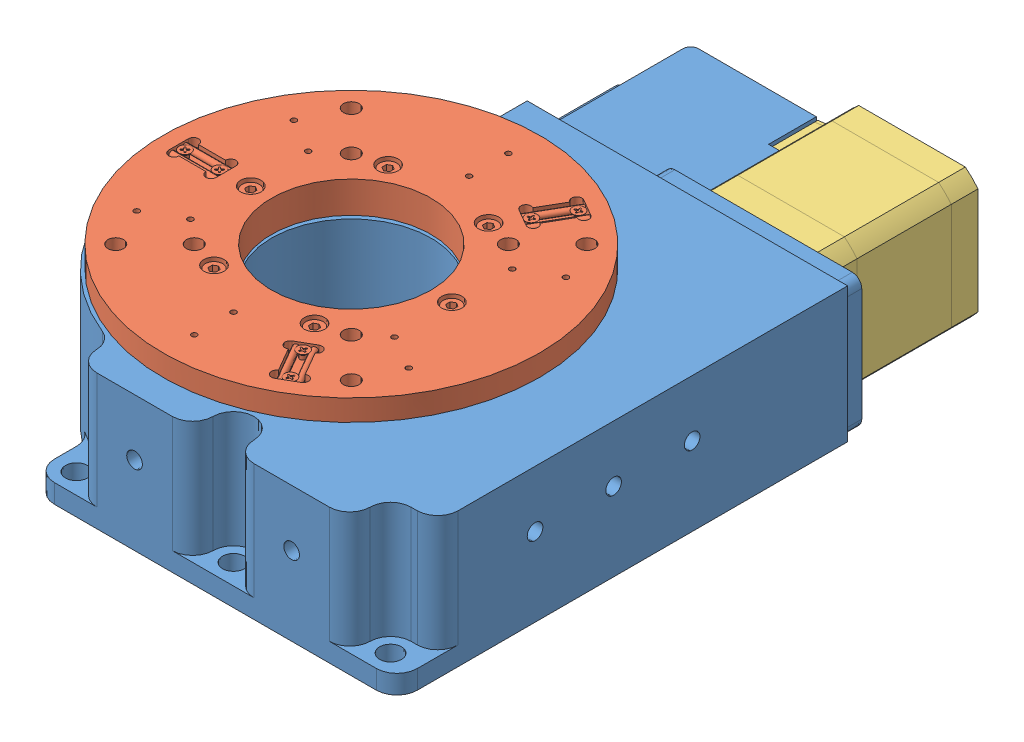
SolidWorks assembly RST120, configuration RST120xK-T3A. Lengths in mm.
Overall size (144.5 50 195.54).
3 component instances, 3 part files, 9 mates.
Components (placement in the parent):
- RST120_base^RST1204-1: RST120_base^RST1204 [RST120-T3A] x (0 0 1) z (-1 0 0) (virtual)
- RST120_top^RST1204-1: RST120_top^RST1204 [Default] x (0 0 1) z (-1 0 0) (virtual)
- NMS17_motor^RST1204-1: NMS17_motor^RST1204 [RST] at (52 21.5 -79.5) x (-1 0 0) z (0 0 1) (virtual)
Mates (geometry in assembly coordinates):
- Coincident1: coincident aligned: plane of ?; plane of assembly through (0 0 0) normal (0 1 0)
- Coincident11: coincident: point of ?
- Coincident4: coincident anti-aligned: plane of ? through (80 3.5 -79.5) normal (0 0 -1); plane of NMS17_motor^RST1204-1 through (52 21.5 -79.5) normal (0 0 1)
- Concentric1: concentric: cylinder of ? through (52 21.5 -79.5) axis (0 0 1) radius 11; point of NMS17_motor^RST1204-1
- Parallel1: parallel anti-aligned: plane of NMS17_motor^RST1204-1; plane of assembly through (0 0 0) normal (0 1 0)
- Coincident7: coincident anti-aligned: plane of ? through (0 0 0) normal (-1 0 0); plane of assembly through (0 0 0) normal (1 0 0)
- Coincident8: coincident aligned: plane of ?; plane of assembly through (0 0 0) normal (0 1 0)
- Coincident9: coincident aligned: plane of ? through (0 0 0) normal (0 0 1); plane of assembly through (0 0 0) normal (0 0 1)
- Home Position: coincident anti-aligned: plane of ? through (0 0 0) normal (-1 0 0); plane of assembly through (0 0 0) normal (1 0 0)
